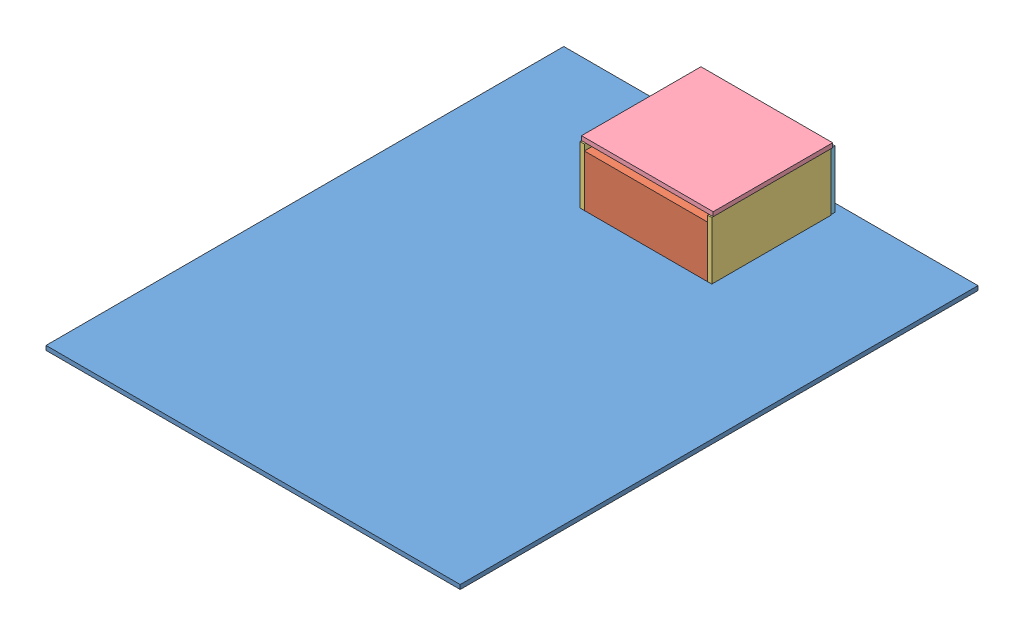
SolidWorks assembly BBTestBench, configuration Default. Lengths in mm.
Overall size (609.6 97.54 762).
6 component instances, 5 part files, 15 mates.
Components (placement in the parent):
- Test Bench-1: Test Bench [Default] at (-90.2259 298.9627 849.6522) size (609.6 6.35 762)
- Battery-1: Battery [Default] at (134.0796 381.2587 114.752) x (0 -1 0) z (-1 0 0) size (75.95 166.88 181.1)
- BBSide-1: BBSide [Default] at (315.1816 390.1487 281.63) x (0 -1 0) z (0 0 1) size (84.84 6.35 175.77)
- BBTop-1: BBTop [Default] at (127.7296 390.1487 279.492) size (193.8 6.35 175.77)
- BBSide-3: BBSide [Default] at (127.7296 390.1487 281.63) x (0 -1 0) z (0 0 1) size (84.84 6.35 175.77)
- BBRear-4: BBRear [Default] at (130.7246 390.1487 105.862) x (1 0 0) z (0 1 0) size (189.99 6.35 84.84)
Mates (geometry in assembly coordinates):
- Coincident1: coincident anti-aligned: plane of Test Bench-1 through (-90.2259 305.3127 849.6522) normal (0 1 0); plane of Battery-1 through (134.0796 305.3127 281.63) normal (0 -1 0)
- Parallel1: parallel aligned: plane of Test Bench-1 through (-90.2259 305.3127 849.6522) normal (0 0 1); plane of Battery-1 through (134.0796 381.2587 281.63) normal (0 0 1)
- Coincident3: coincident anti-aligned: plane of Battery-1 through (315.1816 381.2587 281.63) normal (1 0 0); plane of BBSide-1 through (315.1816 390.1487 281.63) normal (-1 0 0)
- Coincident4: coincident anti-aligned: plane of Test Bench-1 through (-90.2259 305.3127 849.6522) normal (0 1 0); plane of BBSide-1 through (321.5316 305.3127 281.63) normal (0 -1 0)
- Coincident5: coincident aligned: plane of Battery-1 through (134.0796 381.2587 281.63) normal (0 0 1); plane of BBSide-1 through (321.5316 390.1487 281.63) normal (0 0 1)
- Coincident6: coincident anti-aligned: plane of BBSide-1 through (321.5316 390.1487 281.63) normal (0 1 0); plane of BBTop-1 through (127.7296 390.1487 279.492) normal (0 -1 0)
- Coincident7: coincident anti-aligned: plane of BBSide-1 through (321.5316 390.1487 281.63) normal (0 1 0); plane of BBTop-1 through (127.7296 390.1487 279.492) normal (0 -1 0)
- Coincident8: coincident aligned: plane of BBSide-1 through (321.5316 390.1487 281.63) normal (1 0 0); plane of BBTop-1 through (321.5316 396.4987 279.492) normal (1 0 0)
- Lock2: lock: unknown of Test Bench-1; unknown of Battery-1
- Coincident14: coincident anti-aligned: plane of Battery-1 through (134.0796 381.2587 281.63) normal (-1 0 0); plane of BBSide-3 through (134.0796 390.1487 281.63) normal (1 0 0)
- Coincident15: coincident anti-aligned: plane of Test Bench-1 through (-90.2259 305.3127 849.6522) normal (0 1 0); plane of BBSide-3 through (134.0796 305.3127 281.63) normal (0 -1 0)
- Coincident16: coincident aligned: plane of Battery-1 through (134.0796 381.2587 281.63) normal (0 0 1); plane of BBSide-3 through (134.0796 390.1487 281.63) normal (0 0 1)
- Coincident23: coincident anti-aligned: plane of BBSide-1 through (321.5316 390.1487 105.862) normal (0 0 -1); plane of BBRear-4 through (130.7246 390.1487 105.862) normal (0 0 1)
- Coincident24: coincident anti-aligned: plane of Test Bench-1 through (-90.2259 305.3127 849.6522) normal (0 1 0); plane of BBRear-4 through (130.7246 305.3127 99.512) normal (0 -1 0)
- Parallel6: parallel aligned: plane of BBSide-1 through (321.5316 390.1487 281.63) normal (1 0 0); plane of BBRear-4 through (320.7166 390.1487 99.512) normal (1 0 0)
